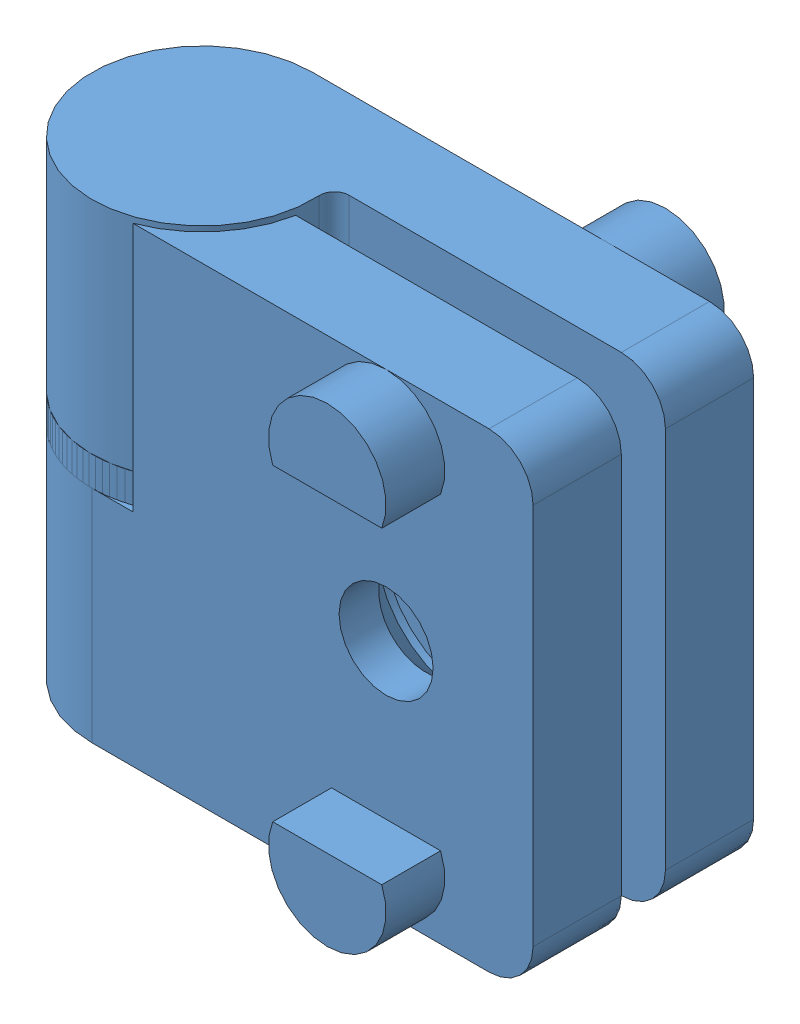
SolidWorks assembly Hinge, configuration Default. Lengths in mm.
Overall size (37.5 32 23).
2 component instances, 1 part files, 0 mates.
Components (placement in the parent):
- 1.62.41L-1: 1.62.41L [Default] at (-9.8678 -5.1025 2.018) size (37.5 32 19)
- 1.62.41L-2: 1.62.41L [Default] at (-9.8678 -5.1025 2.018) x (1 0 0) z (0 0 -1) size (37.5 32 19)
